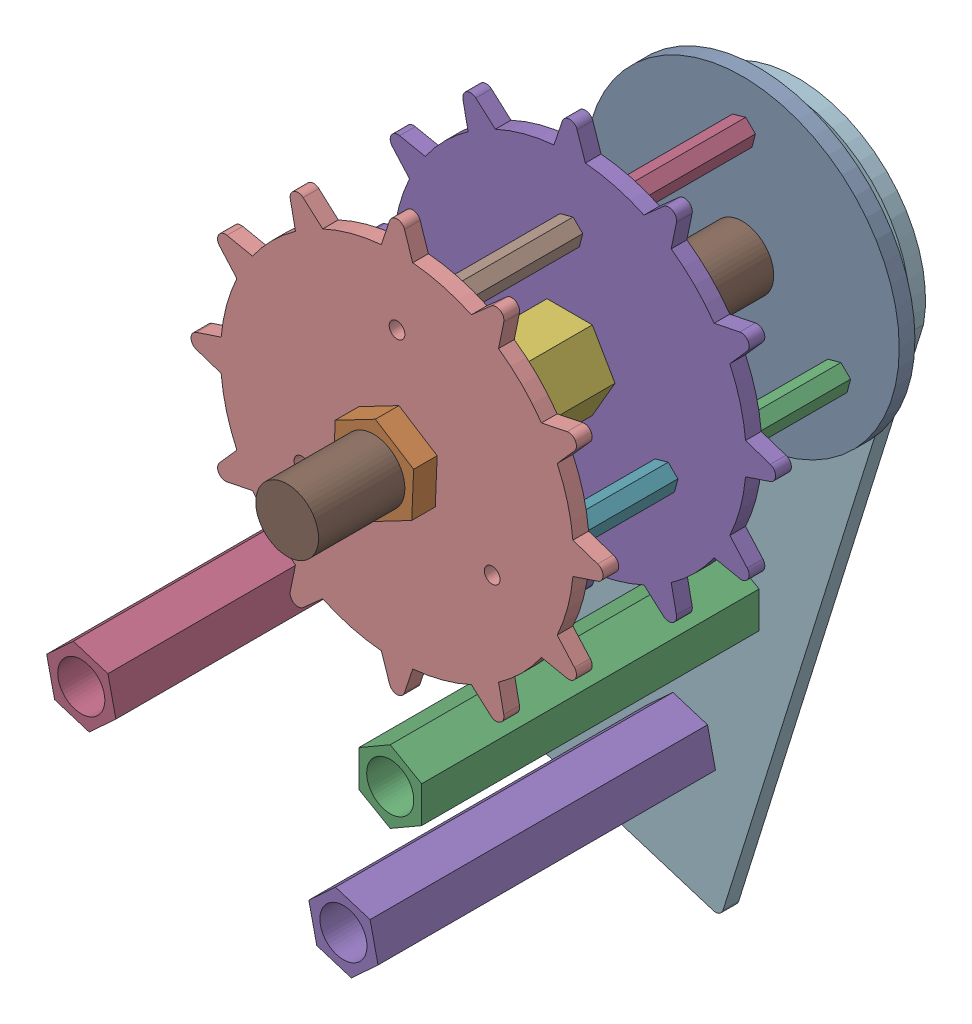
SolidWorks assembly 镜向传动轮1, configuration 默认. Lengths in mm.
Overall size (90.9 107.76 70).
17 component instances, 8 part files, 26 mates.
Components (placement in the parent):
- 镜向外侧圆板-1: 镜向外侧圆板 [默认] at (-112.3007 -16.3228 1) size (40 40 2)
- 镜向齿铜柱-1: 镜向齿铜柱 [默认] at (-124.425 -23.3228 21) size (3.34 3.35 20)
- 镜向齿铜柱-2: 镜向齿铜柱 [默认] at (-100.1763 -23.3228 21) x (-0.5 0.866025 0) z (0 0 1) size (3.34 3.35 20)
- 镜向齿铜柱-3: 镜向齿铜柱 [默认] at (-112.3007 -2.3228 21) x (-0.5 -0.866025 0) z (0 0 1) size (3.34 3.35 20)
- 镜向齿-1: 镜向齿 [默认] at (-112.3007 -16.3228 23) size (52.5 52.5 2)
- 镜向齿内测铜柱-1: 镜向齿内测铜柱 [默认] at (-112.3007 -16.3228 43) size (11.55 10 20)
- 镜向齿铜柱-4: 镜向齿铜柱 [默认] at (-100.1763 -23.3228 43) x (-0.5 0.866025 0) z (0 0 1) size (3.34 3.35 20)
- 镜向齿铜柱-5: 镜向齿铜柱 [默认] at (-112.3007 -2.3228 43) x (-0.5 -0.866025 0) z (0 0 1) size (3.34 3.35 20)
- 镜向齿铜柱-6: 镜向齿铜柱 [默认] at (-124.425 -23.3228 43) size (3.34 3.35 20)
- 镜向齿-2: 镜向齿 [默认] at (-112.3007 -16.3228 45) size (52.5 52.5 2)
- 镜向传动轮螺栓-1: 镜向传动轮螺栓 [默认] at (-112.3007 -16.3228 59) x (-0.980386 -0.197089 0) z (0 0 1) size (12.15 13.85 70)
- 镜向最外侧支撑板-1: 镜向最外侧支撑板 [默认] at (-120.0559 -95.5444 -4) x (0.954528 -0.29812 0) z (0 0 1) size (59.6 94.28 2)
- 镜向8M螺母-1: 镜向8M螺母 [默认] at (-112.3007 -16.3228 -1) x (0.96573 0.25955 0) z (0 0 1) size (10.23 11.54 3)
- 镜向8M螺母-2: 镜向8M螺母 [默认] at (-112.3007 -16.3228 48) size (10.23 11.54 3)
- 镜向43铜柱-1: 镜向43铜柱 [默认] at (-119.167 -59.1547 39) x (0.999179 -0.040516 0) z (0 0 1) size (8.18 9.23 43)
- 镜向43铜柱-2: 镜向43铜柱 [默认] at (-158.5379 -67.8111 39) x (-0.336549 -0.941666 0) z (0 0 1) size (8.18 9.23 43)
- 镜向43铜柱-3: 镜向43铜柱 [默认] at (-125.1294 -78.2453 39) x (-0.336549 -0.941666 0) z (0 0 1) size (8.18 9.23 43)
Mates (geometry in assembly coordinates):
- 同心1: concentric: cylinder of assembly; cylinder of assembly; cylinder of 镜向外侧圆板-1 through (-124.425 -23.3228 1) axis (0 0 -1) radius 1; cylinder of 镜向齿铜柱-1 through (-124.425 -23.3228 21) axis (0 0 -1) radius 1
- 重合1: coincident: plane of assembly; plane of assembly; plane of 镜向外侧圆板-1 through (-112.3007 -16.3228 1) normal (0 0 1); plane of 镜向齿铜柱-1 through (-124.425 -23.3228 1) normal (0 0 -1)
- 同心2: concentric: cylinder of assembly; cylinder of assembly; cylinder of 镜向齿铜柱-3 through (-112.3007 -2.3228 21) axis (0 0 -1) radius 1; cylinder of 镜向齿-1 through (-112.3007 -2.3228 23) axis (0 0 -1) radius 1
- 重合2: coincident: plane of assembly; plane of assembly; plane of 镜向齿铜柱-3 through (-112.3007 -2.3228 21) normal (0 0 1); plane of 镜向齿-1 through (-112.3007 -16.3228 21) normal (0 0 -1)
- 同心3: concentric: cylinder of assembly; cylinder of assembly; cylinder of 镜向齿铜柱-2 through (-100.1763 -23.3228 21) axis (0 0 -1) radius 1; cylinder of 镜向齿-1 through (-100.1763 -23.3228 23) axis (0 0 -1) radius 1
- 同心4: concentric: cylinder of assembly; cylinder of assembly; cylinder of 镜向外侧圆板-1 through (-100.1763 -23.3228 1) axis (0 0 -1) radius 1; cylinder of 镜向齿铜柱-2 through (-100.1763 -23.3228 21) axis (0 0 -1) radius 1
- 同心5: concentric: cylinder of assembly; cylinder of assembly; cylinder of 镜向齿-1 through (-112.3007 -16.3228 23) axis (0 0 -1) radius 4; cylinder of 镜向齿内测铜柱-1 through (-112.3007 -16.3228 43) axis (0 0 -1) radius 4
- 重合3: coincident: plane of assembly; plane of assembly; plane of 镜向齿-1 through (-112.3007 -16.3228 23) normal (0 0 1); plane of 镜向齿内测铜柱-1 through (-112.3007 -16.3228 23) normal (0 0 -1)
- 同心6: concentric: cylinder of assembly; cylinder of assembly; cylinder of 镜向齿-1 through (-100.1763 -23.3228 23) axis (0 0 -1) radius 1; cylinder of 镜向齿铜柱-4 through (-100.1763 -23.3228 43) axis (0 0 -1) radius 1
- 重合4: coincident: plane of assembly; plane of assembly; plane of 镜向齿-1 through (-112.3007 -16.3228 23) normal (0 0 1); plane of 镜向齿铜柱-4 through (-100.1763 -23.3228 23) normal (0 0 -1)
- 同心7: concentric: cylinder of assembly; cylinder of assembly; cylinder of 镜向齿铜柱-4 through (-100.1763 -23.3228 43) axis (0 0 -1) radius 1; cylinder of 镜向齿-2 through (-100.1763 -23.3228 45) axis (0 0 -1) radius 1
- 同心8: concentric: cylinder of assembly; cylinder of assembly; cylinder of 镜向齿铜柱-5 through (-112.3007 -2.3228 43) axis (0 0 -1) radius 1; cylinder of 镜向齿-2 through (-112.3007 -2.3228 45) axis (0 0 -1) radius 1
- 重合5: coincident: plane of assembly; plane of assembly; plane of 镜向齿铜柱-5 through (-112.3007 -2.3228 43) normal (0 0 1); plane of 镜向齿-2 through (-112.3007 -16.3228 43) normal (0 0 -1)
- 同心9: concentric: cylinder of assembly; cylinder of assembly; cylinder of 镜向齿内测铜柱-1 through (-112.3007 -16.3228 43) axis (0 0 -1) radius 4; cylinder of 镜向传动轮螺栓-1 through (-112.3007 -16.3228 -6) axis (0 0 1) radius 4
- 重合6: coincident: plane of assembly; plane of assembly; plane of 镜向传动轮螺栓-1 through (-112.3007 -16.3228 -6) normal (0 0 1); plane of 镜向最外侧支撑板-1 through (-120.0559 -95.5444 -6) normal (0 0 -1)
- 同心10: concentric: cylinder of assembly; cylinder of assembly; cylinder of 镜向传动轮螺栓-1 through (-112.3007 -16.3228 -6) axis (0 0 1) radius 4; cylinder of 镜向8M螺母-1 through (-112.3007 -16.3228 -1) axis (0 0 -1) radius 4
- 重合7: coincident: plane of assembly; plane of assembly; plane of 镜向最外侧支撑板-1 through (-120.0559 -95.5444 -4) normal (0 0 1); plane of 镜向8M螺母-1 through (-112.3007 -16.3228 -4) normal (0 0 -1)
- 重合8: coincident: plane of assembly; plane of assembly; plane of 镜向外侧圆板-1 through (-112.3007 -16.3228 -1) normal (0 0 -1); plane of 镜向8M螺母-1 through (-112.3007 -16.3228 -1) normal (0 0 1)
- 同心11: concentric: cylinder of assembly; cylinder of assembly; cylinder of 镜向传动轮螺栓-1 through (-112.3007 -16.3228 -6) axis (0 0 1) radius 4; cylinder of 镜向8M螺母-2 through (-112.3007 -16.3228 48) axis (0 0 -1) radius 4
- 重合9: coincident: plane of assembly; plane of assembly; plane of 镜向齿-2 through (-112.3007 -16.3228 45) normal (0 0 1); plane of 镜向8M螺母-2 through (-112.3007 -16.3228 45) normal (0 0 -1)
- 同心12: concentric: cylinder of assembly; cylinder of assembly; cylinder of 镜向最外侧支撑板-1 through (-119.167 -59.1547 -4) axis (0 0 -1) radius 3; cylinder of 镜向43铜柱-1 through (-119.167 -59.1547 39.001) axis (0 0 -1) radius 3
- 重合10: coincident: plane of assembly; plane of assembly; plane of 镜向最外侧支撑板-1 through (-120.0559 -95.5444 -4) normal (0 0 1); plane of 镜向43铜柱-1 through (-119.167 -59.1547 -4) normal (0 0 -1)
- 同心13: concentric: cylinder of assembly; cylinder of assembly; cylinder of 镜向最外侧支撑板-1 through (-125.1294 -78.2453 -4) axis (0 0 -1) radius 3; cylinder of 镜向43铜柱-3 through (-125.1294 -78.2453 39.001) axis (0 0 -1) radius 3
- 重合11: coincident: plane of assembly; plane of assembly; plane of 镜向最外侧支撑板-1 through (-120.0559 -95.5444 -4) normal (0 0 1); plane of 镜向43铜柱-3 through (-125.1294 -78.2453 -4) normal (0 0 -1)
- 同心14: concentric: cylinder of assembly; cylinder of assembly; cylinder of 镜向最外侧支撑板-1 through (-158.5379 -67.8111 -4) axis (0 0 -1) radius 3; cylinder of 镜向43铜柱-2 through (-158.5379 -67.8111 39.001) axis (0 0 -1) radius 3
- 重合12: coincident: plane of assembly; plane of assembly; plane of 镜向最外侧支撑板-1 through (-120.0559 -95.5444 -4) normal (0 0 1); plane of 镜向43铜柱-2 through (-158.5379 -67.8111 -4) normal (0 0 -1)
